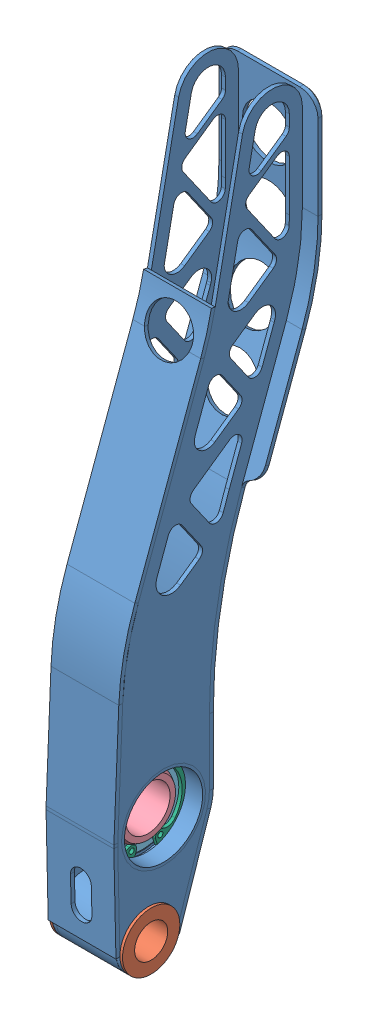
SolidWorks assembly PedalBrake, configuration Default. Lengths in mm.
Overall size (38 315.4 95.66).
9 component instances, 6 part files, 14 mates.
Components (placement in the parent):
- PedalBrake2-1: PedalBrake2 [Finished Design] at origin size (38 315.4 95.66)
- PedalBushing-1: PedalBushing [Default] at (14 79.0909 -303.7744) x (0 0 1) z (-1 0 0) size (22 22 14)
- PedalBushing-2: PedalBushing [Default] at (-14 79.0909 -303.7744) x (0 0.945854 0.324594) z (1 0 0) size (22 22 14)
- PedalPadBrake-1: PedalPadBrake [Default] x (0 0 -1) z (1 0 0) size (23.29 116.75 36)
- SphericalBearingGE17C-1: SphericalBearingGE17C [Default] at (0 116.8675 -309.5268) x (0 0 -1) z (1 0 0) size (30 32.6 22.58)
  - SphericalBearingBallGE17C-1: SphericalBearingBallGE17C [Default] at origin size (25.4 32.6 22.58)
  - SphericalBeaingRaceGE17C-1: SphericalBeaingRaceGE17C [Default] at origin size (30 30 10)
- basic internal retaining ring_AI-1: basic internal retaining ring_AI [B27.1 - NA2-118] at (-5 116.8675 -309.5268) x (0 0 -1) z (1 0 0) size (31.88 31.22 1.27)
- basic internal retaining ring_AI-2: basic internal retaining ring_AI [B27.1 - NA2-118] at (5 116.8675 -309.5268) x (0 0 1) z (-1 0 0) size (31.88 31.22 1.27)
Mates (geometry in assembly coordinates):
- Concentric1: concentric: cylinder of PedalBushing-1 through (14 79.0909 -303.7744) axis (1 0 0) radius 8; cylinder of PedalBrake2-1 through (62.4117 79.0909 -303.7744) axis (-1 0 0) radius 8
- Coincident1: coincident: plane of PedalBrake2-1 through (13 326.2909 -351.1744) normal (1 0 0); plane of PedalBushing-1 through (13 90.0909 -303.7744) normal (-1 0 0)
- Coincident2: coincident: plane of PedalBrake2-1 through (-13 326.2909 -351.1744) normal (-1 0 0); plane of PedalBushing-2 through (-13 75.5204 -293.37) normal (1 0 0)
- Concentric11: concentric: cylinder of PedalBrake2-1 through (62.4117 79.0909 -303.7744) axis (-1 0 0) radius 8; cylinder of PedalBushing-2 through (-14 79.0909 -303.7744) axis (-1 0 0) radius 8
- InPlace1: in place: plane of PedalPadBrake-1 through (0 0 0) normal (1 0 0); moOrthogonalPlaneRef_w of PedalPadBrake-1 through (-55 0 0) axis (0 0 1); plane of PedalPadBrake-1 through (0 0 0) normal (0 0 -1); unknown of PedalPadBrake-1
- Coincident8: coincident: plane of PedalPadBrake-1; plane of assembly
- Coincident9: coincident: plane of PedalPadBrake-1 through (0 0 0) normal (0 1 0); moOrthogonalPlaneRef_w of assembly
- Coincident10: coincident: plane of PedalPadBrake-1 through (0 0 0) normal (0 0 -1); moOrthogonalPlaneRef_w of assembly
- Concentric12: concentric: cylinder of PedalBrake2-1 through (62.4117 116.8675 -309.5268) axis (-1 0 0) radius 15; cylinder of SphericalBearingGE17C-1/SphericalBeaingRaceGE17C-1 through (-5 116.8675 -309.5268) axis (1 0 0) radius 15
- Coincident3: coincident: plane of ? through (0 116.8675 -309.5268) normal (1 0 0); plane of assembly through (0 0 0) normal (1 0 0)
- Concentric13: concentric: cylinder of PedalBrake2-1 through (62.4117 116.8675 -309.5268) axis (-1 0 0) radius 15; cylinder of basic internal retaining ring_AI-1 through (-6.27 116.8675 -309.5268) axis (1 0 0) radius 15.9385
- Coincident4: coincident: plane of PedalBrake2-1 through (-5 116.8675 -309.5268) normal (-1 0 0); plane of basic internal retaining ring_AI-1 through (-5 116.8675 -309.5268) normal (1 0 0)
- Concentric14: concentric: cylinder of PedalBrake2-1 through (62.4117 116.8675 -309.5268) axis (-1 0 0) radius 15; cylinder of basic internal retaining ring_AI-2 through (6.27 116.8675 -309.5268) axis (-1 0 0) radius 15.9385
- Coincident5: coincident: plane of PedalBrake2-1 through (5 116.8675 -309.5268) normal (1 0 0); plane of basic internal retaining ring_AI-2 through (5 116.8675 -309.5268) normal (-1 0 0)
